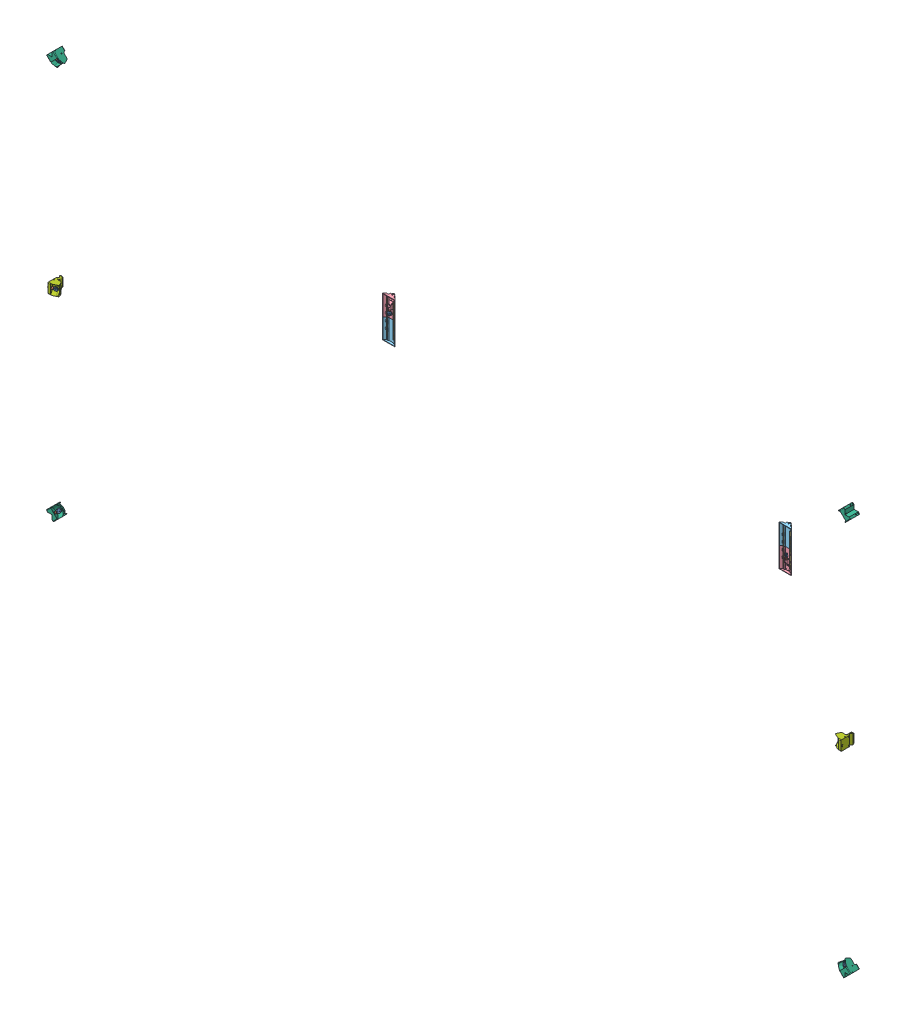
SolidWorks assembly Licht, configuration Standard. Lengths in mm.
Overall size (6086.22 3086.22 1125.76).
38 component instances, 7 part files, 21 mates.
Components (placement in the parent):
- Center-Decke-1: Center-Decke [Standard] at (-146.4358 126.2028 306) x (-1 0 0) z (0 0 1) size (95 306 46.66)
  - G4 LED-1: G4 LED [Standard] at (-69.7688 71.9428 102.8196) x (-0.866025 0 -0.5) z (0 1 0) size (30 9.9 34.79)
  - G4 Sockel-1: G4 Sockel [Standard] at (-69.3938 46.9428 102.1701) x (0.258819 0 0.965926) z (0 1 0) size (16 16 33.5)
  - LED-Bar-1: LED-Bar [Standard] at (-39.0865 238.9428 95.1701) x (0 1 0) z (1 0 0) size (250 3.5 8)
  - LED-Bar-2: LED-Bar [Standard] at (-91.7012 238.9428 95.1701) x (0 1 0) z (1 0 0) size (250 3.5 8)
  - Center-Decke-Gehäuse-Left-1: Center-Decke-Gehäuse-Left [Standard] at (-69.3938 -38.0572 77.1701) size (95 157.8 44)
  - Center-Decke-Gehäuse-Right-1: Center-Decke-Gehäuse-Right [Standard] at (-69.3938 267.9428 77.1701) x (-1 0 0) z (0 0 1) size (95 153 41)
- Center-Decke-2: Center-Decke [Standard] at (2992.3519 -103.6828 306) size (95 306 46.66)
  - G4 LED-1: G4 LED [Standard] at (-69.7688 71.9428 102.8196) x (-0.866025 0 -0.5) z (0 1 0) size (30 9.9 34.79)
  - G4 Sockel-1: G4 Sockel [Standard] at (-69.3938 46.9428 102.1701) x (0.258819 0 0.965926) z (0 1 0) size (16 16 33.5)
  - LED-Bar-1: LED-Bar [Standard] at (-39.0865 238.9428 95.1701) x (0 1 0) z (1 0 0) size (250 3.5 8)
  - LED-Bar-2: LED-Bar [Standard] at (-91.7012 238.9428 95.1701) x (0 1 0) z (1 0 0) size (250 3.5 8)
  - Center-Decke-Gehäuse-Left-1: Center-Decke-Gehäuse-Left [Standard] at (-69.3938 -38.0572 77.1701) size (95 157.8 44)
  - Center-Decke-Gehäuse-Right-1: Center-Decke-Gehäuse-Right [Standard] at (-69.3938 267.9428 77.1701) x (-1 0 0) z (0 0 1) size (95 153 41)
- Ecklampe-1: Ecklampe [Standard] at (4414.9801 -1479.6237 1563.1701) x (-0.707107 -0.707107 0) z (0 0 -1) size (76.89 88.28 74.76)
  - Ecke-1: Ecke [Standard] at (0.8049 -12.0874 100) size (76.89 88.28 70)
  - G4 LED-1: G4 LED [Standard] at (0.8049 26.7881 125.3083) x (1 0 0) z (0 0.906308 0.422618) size (30 9.9 34.79)
  - G4 Sockel-1: G4 Sockel [Standard] at (0.8049 3.8135 115.4226) x (0.707107 -0.298836 0.640856) z (0 0.906308 0.422618) size (16 16 33.5)
- Ecklampe-2: Ecklampe [Standard] at (-1567.9257 -1480.7621 1563.1701) x (-0.707107 0.707107 0) z (0 0 -1) size (76.89 88.28 74.76)
  - Ecke-1: Ecke [Standard] at (0.8049 -12.0874 100) size (76.89 88.28 70)
  - G4 LED-1: G4 LED [Standard] at (0.8049 26.7881 125.3083) x (1 0 0) z (0 0.906308 0.422618) size (30 9.9 34.79)
  - G4 Sockel-1: G4 Sockel [Standard] at (0.8049 3.8135 115.4226) x (0.707107 -0.298836 0.640856) z (0 0.906308 0.422618) size (16 16 33.5)
- Ecklampe-3: Ecklampe [Standard] at (4413.8417 1503.282 1563.1701) x (0.707107 -0.707107 0) z (0 0 -1) size (76.89 88.28 74.76)
  - Ecke-1: Ecke [Standard] at (0.8049 -12.0874 100) size (76.89 88.28 70)
  - G4 LED-1: G4 LED [Standard] at (0.8049 26.7881 125.3083) x (1 0 0) z (0 0.906308 0.422618) size (30 9.9 34.79)
  - G4 Sockel-1: G4 Sockel [Standard] at (0.8049 3.8135 115.4226) x (0.707107 -0.298836 0.640856) z (0 0.906308 0.422618) size (16 16 33.5)
- Ecklampe-4: Ecklampe [Standard] at (-1569.0641 1502.1437 1563.1701) x (0.707107 0.707107 0) z (0 0 -1) size (76.89 88.28 74.76)
  - Ecke-1: Ecke [Standard] at (0.8049 -12.0874 100) size (76.89 88.28 70)
  - G4 LED-1: G4 LED [Standard] at (0.8049 26.7881 125.3083) x (1 0 0) z (0 0.906308 0.422618) size (30 9.9 34.79)
  - G4 Sockel-1: G4 Sockel [Standard] at (0.8049 3.8135 115.4226) x (0.707107 -0.298836 0.640856) z (0 0.906308 0.422618) size (16 16 33.5)
- Eingang-1: Eingang [Standard] at (-1550.1495 22.1813 1593.1701) x (0 1 0) z (0 0 -1) size (76.89 75.96 104.76)
  - Zelteingang-1: Zelteingang [Standard] at (-10.9214 -29.8925 100) size (76.89 62.78 100)
  - G4 LED-1: G4 LED [Standard] at (-10.9214 8.9831 125.3083) x (1 0 0) z (0 0.906308 0.422618) size (30 9.9 34.79)
  - G4 Sockel-1: G4 Sockel [Standard] at (-10.9214 -13.9916 115.4226) x (-0.707107 0.298836 -0.640856) z (0 0.906308 0.422618) size (16 16 33.5)
- Eingang-2: Eingang [Standard] at (4396.0655 0.3386 1593.1701) x (0 -1 0) z (0 0 -1) size (76.89 75.96 104.76)
  - Zelteingang-1: Zelteingang [Standard] at (-10.9214 -29.8925 100) size (76.89 62.78 100)
  - G4 LED-1: G4 LED [Standard] at (-10.9214 8.9831 125.3083) x (1 0 0) z (0 0.906308 0.422618) size (30 9.9 34.79)
  - G4 Sockel-1: G4 Sockel [Standard] at (-10.9214 -13.9916 115.4226) x (-0.707107 0.298836 -0.640856) z (0 0.906308 0.422618) size (16 16 33.5)
Mates (geometry in assembly coordinates):
- Deckungsgleich1: coincident aligned: plane of Center-Decke-1/Center-Decke-Gehäuse-Left-1 through (-62.542 11.26 393.1701) normal (0 0 -1); plane of Center-Decke-2/Center-Decke-Gehäuse-Left-1 through (2908.458 11.26 393.1701) normal (0 0 -1)
- Abstand3: distance = 1000 mm aligned: plane of Center-Decke-1/Center-Decke-Gehäuse-Right-1 through (-91.542 11.26 393.1701) normal (0 0 -1); plane of Ecklampe-4/Ecke-1 through (-1577.042 1511.26 1393.1701) normal (0 0 -1)
- Deckungsgleich10: coincident aligned: plane of Ecklampe-2/Ecke-1 through (-1577.042 -1520.5598 1393.1701) normal (-1 0 0); plane of Ecklampe-4/Ecke-1 through (-1577.042 1511.26 1393.1701) normal (-1 0 0)
- Deckungsgleich11: coincident aligned: plane of Ecklampe-3/Ecke-1 through (4422.958 1511.26 1393.1701) normal (0 1 0); plane of Ecklampe-4/Ecke-1 through (-1608.8618 1511.26 1393.1701) normal (0 1 0)
- Deckungsgleich12: coincident aligned: plane of Ecklampe-1/Ecke-1 through (4454.7778 -1488.74 1393.1701) normal (0 -1 0); plane of Ecklampe-2/Ecke-1 through (-1577.042 -1488.74 1393.1701) normal (0 -1 0)
- Abstand6: distance = 6000 mm anti-aligned: plane of Ecklampe-1/Ecke-1 through (4422.958 -1488.74 1393.1701) normal (1 0 0); plane of Ecklampe-2/Ecke-1 through (-1577.042 -1520.5598 1393.1701) normal (-1 0 0)
- Abstand7: distance = 3000 mm anti-aligned: plane of Ecklampe-2/Ecke-1 through (-1577.042 -1488.74 1393.1701) normal (0 -1 0); plane of Ecklampe-4/Ecke-1 through (-1608.8618 1511.26 1393.1701) normal (0 1 0)
- Deckungsgleich15: coincident aligned: plane of Ecklampe-1/Ecke-1 through (4422.958 -1488.74 1393.1701) normal (1 0 0); plane of Ecklampe-3/Ecke-1 through (4422.958 1543.0798 1393.1701) normal (1 0 0)
- Deckungsgleich18: coincident aligned: plane of Center-Decke-1/Center-Decke-Gehäuse-Right-1 through (-77.042 -141.74 383.1701) normal (0 -1 0); plane of Center-Decke-2/Center-Decke-Gehäuse-Left-1 through (2922.958 -141.74 383.1701) normal (0 -1 0)
- Abstand11: distance = 1500 mm: line of Center-Decke-1/Center-Decke-Gehäuse-Right-1 through (-73.542 11.26 393.1701) axis (-1 0 0); plane of Ecklampe-4/Ecke-1 through (-1608.8618 1511.26 1393.1701) normal (0 1 0)
- Abstand12: distance = 1500 mm: plane of Ecklampe-4/Ecke-1 through (-1577.042 1511.26 1393.1701) normal (-1 0 0); moEndPointRef_w of Center-Decke-1/Center-Decke-Gehäuse-Left-1
- Deckungsgleich22: coincident aligned: plane of Ecklampe-2/Ecke-1 through (-1577.042 -1488.74 1393.1701) normal (0 0 -1); plane of Ecklampe-4/Ecke-1 through (-1577.042 1511.26 1393.1701) normal (0 0 -1)
- Deckungsgleich23: coincident aligned: plane of Ecklampe-1/Ecke-1 through (4422.958 -1488.74 1393.1701) normal (0 0 -1); plane of Ecklampe-2/Ecke-1 through (-1577.042 -1488.74 1393.1701) normal (0 0 -1)
- Deckungsgleich24: coincident aligned: plane of Ecklampe-1/Ecke-1 through (4422.958 -1488.74 1393.1701) normal (0 0 -1); plane of Ecklampe-3/Ecke-1 through (4422.958 1511.26 1393.1701) normal (0 0 -1)
- Abstand13: distance = 3000 mm aligned: plane of Center-Decke-1/Center-Decke-Gehäuse-Left-1 through (-59.542 161.26 383.1701) normal (1 0 0); plane of Center-Decke-2/Center-Decke-Gehäuse-Right-1 through (2940.458 161.26 383.1701) normal (1 0 0)
- Deckungsgleich27: coincident aligned: plane of Ecklampe-4/Ecke-1 through (-1577.042 1511.26 1393.1701) normal (0 0 -1); plane of Eingang-1/Zelteingang-1 through (-1580.042 11.26 1393.1701) normal (0 0 -1)
- Deckungsgleich28: coincident aligned: plane of Ecklampe-3/Ecke-1 through (4422.958 1511.26 1393.1701) normal (0 0 -1); plane of Eingang-2/Zelteingang-1 through (4425.958 11.26 1393.1701) normal (0 0 -1)
- Deckungsgleich29: coincident aligned: plane of Ecklampe-3/Ecke-1 through (4422.958 1543.0798 1393.1701) normal (1 0 0); plane of Eingang-2/Zelteingang-1 through (4422.958 48.76 1393.1701) normal (1 0 0)
- Deckungsgleich30: coincident aligned: plane of Ecklampe-4/Ecke-1 through (-1577.042 1511.26 1393.1701) normal (-1 0 0); plane of Eingang-1/Zelteingang-1 through (-1577.042 -26.24 1393.1701) normal (-1 0 0)
- Deckungsgleich31: coincident aligned: plane of Eingang-1/Zelteingang-1 through (-1577.042 48.76 1393.1701) normal (0 1 0); plane of Eingang-2/Zelteingang-1 through (4417.958 48.76 1393.1701) normal (0 1 0)
- Abstand15: distance = 1500 mm: plane of Ecklampe-3/Ecke-1 through (4422.958 1511.26 1393.1701) normal (0 1 0); moEndPointRef_w of Eingang-2/Zelteingang-1
